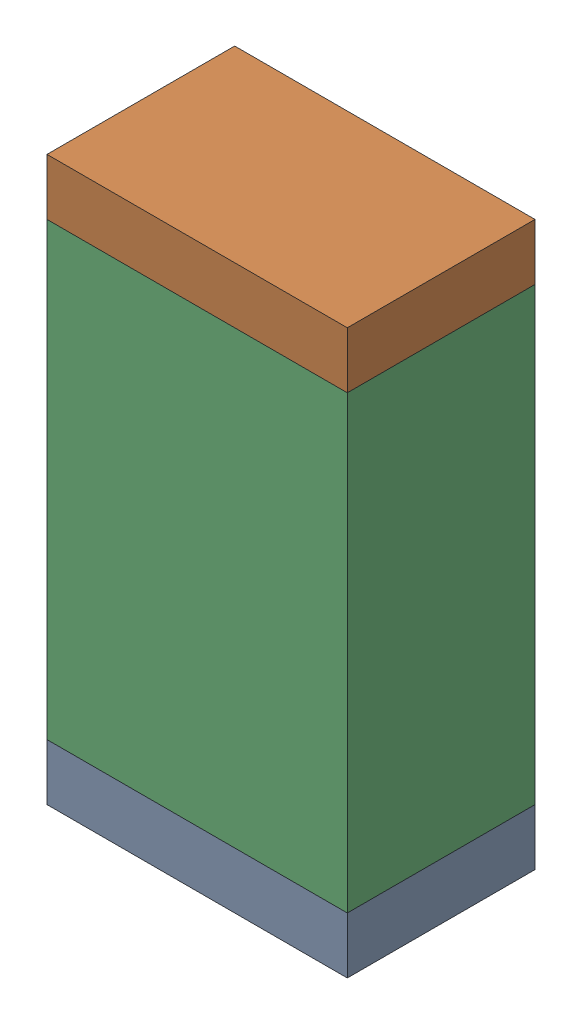
SolidWorks assembly R69, configuration Default. Lengths in mm.
Overall size (0.8 1.5 0.5).
6 component instances, 2 part files, 0 mates.
Components (placement in the parent):
- 810156592-1: 810156592 [Default] at (120.05 75.425 0) size (0.8 0.15 0.5)
  - Extruded_7-1: Extruded_7 [Default] at origin size (0.8 0.15 0.5)
- 810156592-2: 810156592 [Default] at (120.05 76.775 0) size (0.8 0.15 0.5)
  - Extruded_7-1: Extruded_7 [Default] at origin size (0.8 0.15 0.5)
- 810156976-1: 810156976 [Default] at (120.05 76.1 0) size (0.8 1.2 0.5)
  - Extruded_6-1: Extruded_6 [Default] at origin size (0.8 1.2 0.5)
